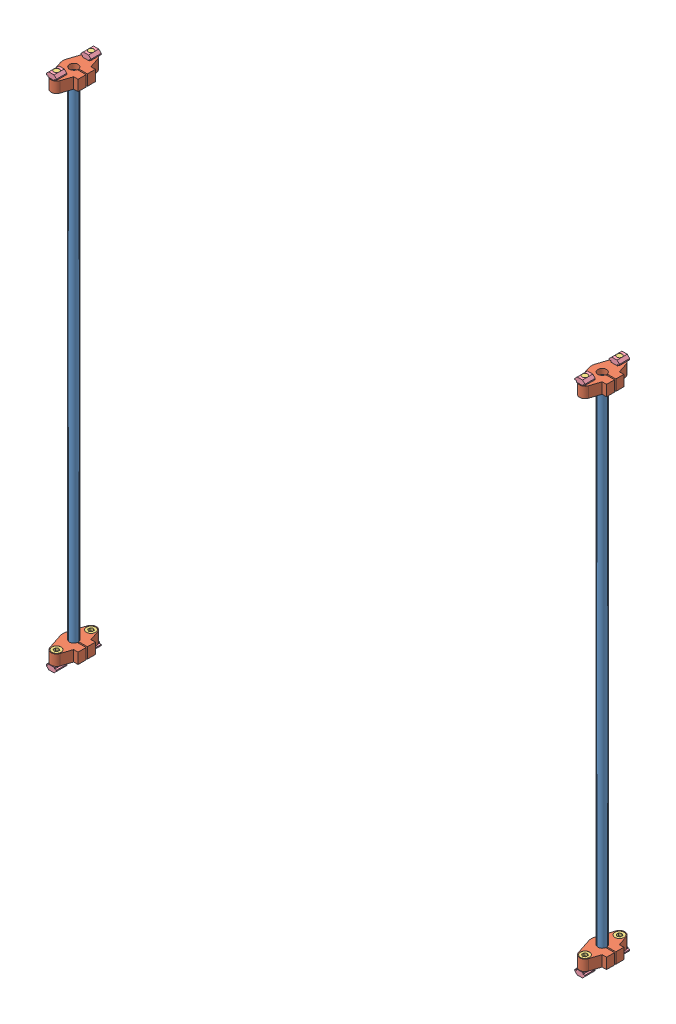
SolidWorks assembly 031X轴活动机构-光轴-1, configuration Default. Lengths in mm.
Overall size (512 480.2 42).
22 component instances, 4 part files, 6 mates.
Components (placement in the parent):
- 光轴8mm465mmXY轴-1: 光轴8mm465mmXY轴 [默认] at (163.5315 6.3639 322.9209) x (1 0 0) z (0 1 0) size (8 8 465)
- SHF8光轴菱型卧式固定支撑座-1: SHF8光轴菱型卧式固定支撑座 [默认] at (163.5315 6.3639 322.9209) x (0 0 -1) z (0 1 0) size (42 22 10)
- SHF8光轴菱型卧式固定支撑座-4: SHF8光轴菱型卧式固定支撑座 [默认] at (163.5315 476.3639 322.9209) x (0 0 1) z (0 -1 0) size (42 22 10)
- SHF8光轴菱型卧式固定支撑座-3: SHF8光轴菱型卧式固定支撑座 [默认] at (653.5315 6.3639 322.9209) x (0 0 -1) z (0 1 0) size (42 22 10)
- 光轴8mm465mmXY轴-2: 光轴8mm465mmXY轴 [默认] at (653.5315 6.3639 322.9209) x (1 0 0) z (0 1 0) size (8 8 465)
- SHF8光轴菱型卧式固定支撑座-5: SHF8光轴菱型卧式固定支撑座 [默认] at (653.5315 476.3639 322.9209) x (0 0 1) z (0 -1 0) size (42 22 10)
- M5_10-1: M5_10 [默认] at (653.5315 481.3639 338.9209) x (1 0 0) z (0 0 -1) size (8.5 14.91 8.5)
- 欧标20M5滑块螺母-1: 欧标20M5滑块螺母 [默认] at (648.7815 481.4639 343.6709) x (0 0 -1) z (-1 0 0) size (9.5 4.5 9.5)
- 欧标20M5滑块螺母-2: 欧标20M5滑块螺母 [默认] at (158.7815 481.4639 343.6709) x (0 0 -1) z (-1 0 0) size (9.5 4.5 9.5)
- 欧标20M5滑块螺母-3: 欧标20M5滑块螺母 [默认] at (648.7815 481.4639 311.6709) x (0 0 -1) z (-1 0 0) size (9.5 4.5 9.5)
- 欧标20M5滑块螺母-4: 欧标20M5滑块螺母 [默认] at (158.7815 481.4639 311.6709) x (0 0 -1) z (-1 0 0) size (9.5 4.5 9.5)
- M5_10-2: M5_10 [默认] at (163.5315 481.3639 338.9209) x (1 0 0) z (0 0 -1) size (8.5 14.91 8.5)
- M5_10-3: M5_10 [默认] at (653.5315 481.3639 306.9209) x (1 0 0) z (0 0 -1) size (8.5 14.91 8.5)
- M5_10-4: M5_10 [默认] at (163.5315 481.3639 306.9209) x (1 0 0) z (0 0 -1) size (8.5 14.91 8.5)
- M5_10-5: M5_10 [默认] at (653.5315 1.3639 338.9209) x (-1 0 0) z (0 0 -1) size (8.5 14.91 8.5)
- 欧标20M5滑块螺母-5: 欧标20M5滑块螺母 [默认] at (658.2815 1.2639 343.6709) x (0 0 -1) z (1 0 0) size (9.5 4.5 9.5)
- 欧标20M5滑块螺母-6: 欧标20M5滑块螺母 [默认] at (168.2815 1.2639 343.6709) x (0 0 -1) z (1 0 0) size (9.5 4.5 9.5)
- 欧标20M5滑块螺母-7: 欧标20M5滑块螺母 [默认] at (658.2815 1.2639 311.6709) x (0 0 -1) z (1 0 0) size (9.5 4.5 9.5)
- 欧标20M5滑块螺母-8: 欧标20M5滑块螺母 [默认] at (168.2815 1.2639 311.6709) x (0 0 -1) z (1 0 0) size (9.5 4.5 9.5)
- M5_10-6: M5_10 [默认] at (163.5315 1.3639 338.9209) x (-1 0 0) z (0 0 -1) size (8.5 14.91 8.5)
- M5_10-7: M5_10 [默认] at (653.5315 1.3639 306.9209) x (-1 0 0) z (0 0 -1) size (8.5 14.91 8.5)
- M5_10-8: M5_10 [默认] at (163.5315 1.3639 306.9209) x (-1 0 0) z (0 0 -1) size (8.5 14.91 8.5)
Mates (geometry in assembly coordinates):
- 重合3: coincident: plane of 光轴8mm465mmXY轴-1 through (163.5315 6.3639 322.9209) normal (0 -1 0); plane of SHF8光轴菱型卧式固定支撑座-1 through (163.5315 6.3639 322.9209) normal (0 -1 0)
- 同心2: concentric: circle of 光轴8mm465mmXY轴-1; circle of SHF8光轴菱型卧式固定支撑座-1
- 重合4: coincident: plane of assembly; plane of assembly; plane of SHF8光轴菱型卧式固定支撑座-5 through (653.5315 471.3639 322.9209) normal (0 -1 0); plane of M5_10-1 through (653.5315 471.3639 338.9209) normal (0 1 0)
- 同心3: concentric: cylinder of assembly; cylinder of assembly; cylinder of SHF8光轴菱型卧式固定支撑座-5 through (653.5315 471.3639 338.9209) axis (0 1 0) radius 2.75; cylinder of M5_10-1 through (653.5315 471.3639 338.9209) axis (0 1 0) radius 2.5
- 同心4: concentric: cylinder of assembly; cylinder of assembly; cylinder of M5_10-1 through (653.5315 471.3639 338.9209) axis (0 1 0) radius 2.5; cylinder of 欧标20M5滑块螺母-1 through (653.5315 481.4639 338.9209) axis (0 -1 0) radius 2.5
- 距离1: distance = 1.8 mm: plane of assembly; plane of assembly; plane of SHF8光轴菱型卧式固定支撑座-5 through (653.5315 476.3639 322.9209) normal (0 1 0); plane of 欧标20M5滑块螺母-1 through (648.7815 478.1639 343.6709) normal (0 -1 0)
